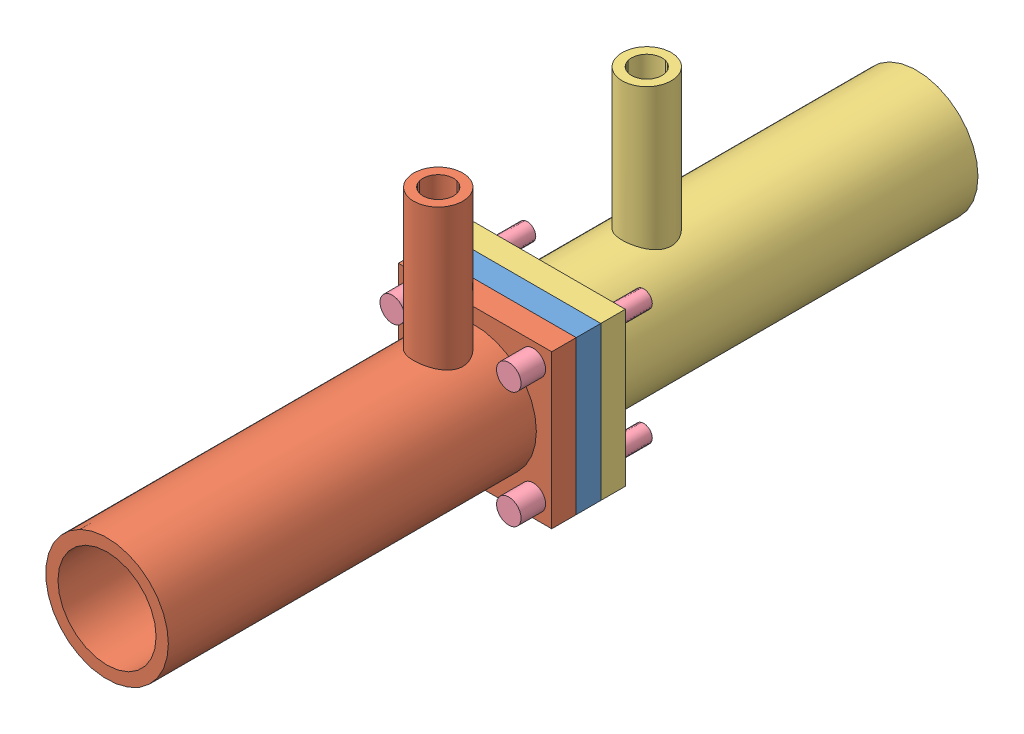
SolidWorks assembly GNG1103-ASSEMBLY1, configuration Default. Lengths in mm.
Overall size (31.75 57.15 167.64).
7 component instances, 4 part files, 12 mates.
Components (placement in the parent):
- GNG1103-PART4-ORIFICEPLATE-1: GNG1103-PART4-ORIFICEPLATE [Default] at (-201.8525 -132.7977 265.0026) size (31.75 31.75 5.08)
- GNG1103-PART2-PROJECT-2: GNG1103-PART2-PROJECT [Default] at (-201.8525 -132.7977 351.3626) size (31.75 57.15 81.28)
- GNG1103-PART3-PROJECT-1: GNG1103-PART3-PROJECT [Default] at (-201.8525 -132.7977 259.9226) size (31.75 57.15 81.28)
- GNG1103-PINS-PROJECT-5: GNG1103-PINS-PROJECT [Default] at (-189.7875 -120.7327 280.2426) size (5.08 5.08 27.94)
- GNG1103-PINS-PROJECT-6: GNG1103-PINS-PROJECT [Default] at (-213.9175 -120.7327 280.2426) size (5.08 5.08 27.94)
- GNG1103-PINS-PROJECT-7: GNG1103-PINS-PROJECT [Default] at (-189.7875 -144.8627 280.2426) size (5.08 5.08 27.94)
- GNG1103-PINS-PROJECT-8: GNG1103-PINS-PROJECT [Default] at (-213.9175 -144.8627 280.2426) size (5.08 5.08 27.94)
Mates (geometry in assembly coordinates):
- Concentric1: concentric anti-aligned: cylinder of GNG1103-PART4-ORIFICEPLATE-1 through (-213.9175 -120.7327 261.1926) axis (0 0 1) radius 1.905; cylinder of GNG1103-PART2-PROJECT-2 through (-213.9175 -120.7327 278.9726) axis (0 0 -1) radius 1.905
- Coincident1: coincident anti-aligned: plane of GNG1103-PART4-ORIFICEPLATE-1 through (-201.8525 -132.7977 270.0826) normal (0 0 1); plane of GNG1103-PART2-PROJECT-2 through (-201.8525 -132.7977 270.0826) normal (0 0 -1)
- Concentric2: concentric aligned: cylinder of GNG1103-PART4-ORIFICEPLATE-1 through (-213.9175 -144.8627 261.1926) axis (0 0 1) radius 1.905; cylinder of GNG1103-PART3-PROJECT-1 through (-213.9175 -144.8627 209.1226) axis (0 0 1) radius 1.905
- Coincident2: coincident anti-aligned: plane of GNG1103-PART4-ORIFICEPLATE-1 through (-201.8525 -132.7977 265.0026) normal (0 0 -1); plane of GNG1103-PART3-PROJECT-1 through (-201.8525 -132.7977 265.0026) normal (0 0 1)
- Concentric4: concentric anti-aligned: cylinder of GNG1103-PART2-PROJECT-2 through (-189.7875 -120.7327 278.9726) axis (0 0 -1) radius 1.905; cylinder of GNG1103-PINS-PROJECT-5 through (-189.7875 -120.7327 252.3026) axis (0 0 1) radius 1.778
- Coincident4: coincident anti-aligned: plane of GNG1103-PART2-PROJECT-2 through (-201.8525 -132.7977 275.1626) normal (0 0 1); plane of GNG1103-PINS-PROJECT-5 through (-189.7875 -120.7327 275.1626) normal (0 0 -1)
- Concentric5: concentric anti-aligned: cylinder of GNG1103-PART2-PROJECT-2 through (-189.7875 -144.8627 278.9726) axis (0 0 -1) radius 1.905; cylinder of GNG1103-PINS-PROJECT-7 through (-189.7875 -144.8627 252.3026) axis (0 0 1) radius 1.778
- Coincident5: coincident anti-aligned: plane of GNG1103-PART2-PROJECT-2 through (-201.8525 -132.7977 275.1626) normal (0 0 1); plane of GNG1103-PINS-PROJECT-7 through (-189.7875 -144.8627 275.1626) normal (0 0 -1)
- Concentric6: concentric anti-aligned: cylinder of GNG1103-PART2-PROJECT-2 through (-213.9175 -120.7327 278.9726) axis (0 0 -1) radius 1.905; cylinder of GNG1103-PINS-PROJECT-6 through (-213.9175 -120.7327 252.3026) axis (0 0 1) radius 1.778
- Coincident6: coincident anti-aligned: plane of GNG1103-PART2-PROJECT-2 through (-201.8525 -132.7977 275.1626) normal (0 0 1); plane of GNG1103-PINS-PROJECT-6 through (-213.9175 -120.7327 275.1626) normal (0 0 -1)
- Concentric7: concentric anti-aligned: cylinder of GNG1103-PART2-PROJECT-2 through (-213.9175 -144.8627 278.9726) axis (0 0 -1) radius 1.905; cylinder of GNG1103-PINS-PROJECT-8 through (-213.9175 -144.8627 252.3026) axis (0 0 1) radius 1.778
- Coincident7: coincident anti-aligned: plane of GNG1103-PART2-PROJECT-2 through (-201.8525 -132.7977 275.1626) normal (0 0 1); plane of GNG1103-PINS-PROJECT-8 through (-213.9175 -144.8627 275.1626) normal (0 0 -1)
